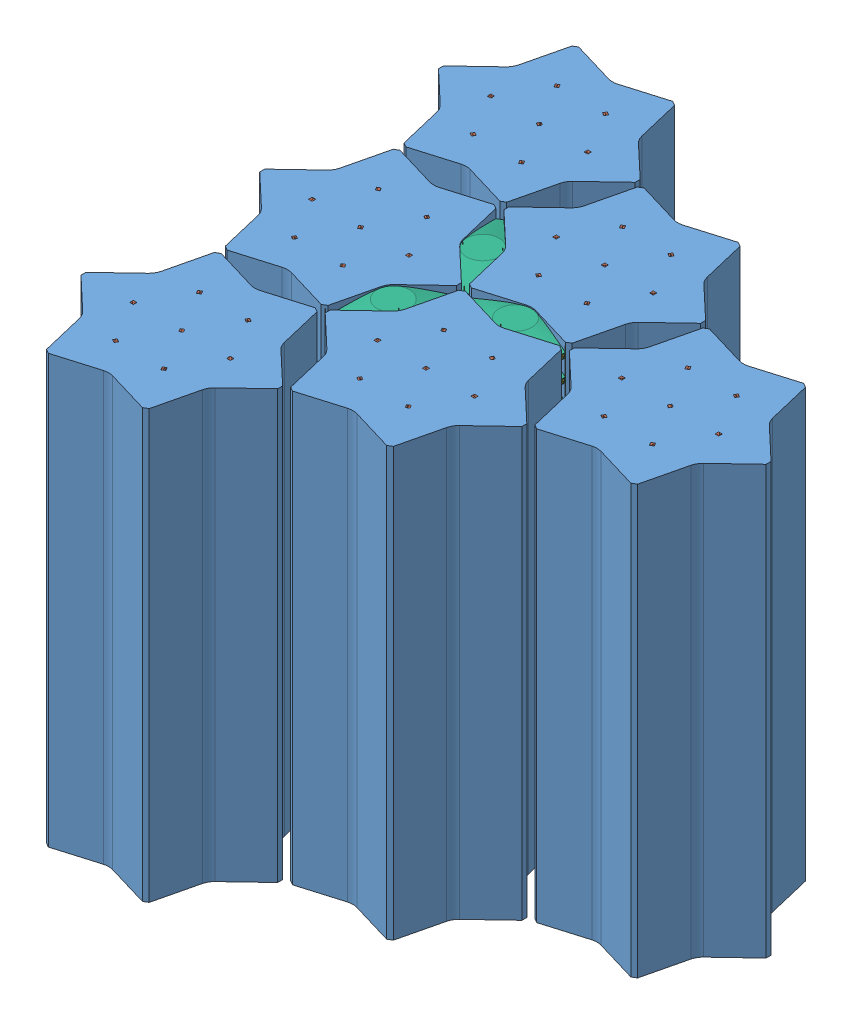
SolidWorks assembly Array-3, configuration 默认. Lengths in mm.
Overall size (1956.05 1510.25 2154.73).
477 component instances, 7 part files, 6 mates.
Components (placement in the parent):
- SArUnit-1: SArUnit [默认] at (117.0902 -977.6752 1500.5) size (690 1500.5 606.22)
  - SArContainer-1: SArContainer [默认] at origin size (690 1500 606.22)
  - SiPMArray-Ar-2: SiPMArray-Ar [默认] at (0 1500 0) size (12 0.5 12)
  - SiPMArray-Ar-3: SiPMArray-Ar [默认] at (-170 1500 0) size (12 0.5 12)
  - SiPMArray-Ar-4: SiPMArray-Ar [默认] at (-85 1500 147.2243) x (0.5 0 -0.866025) z (0.866025 0 0.5) size (12 0.5 12)
  - SiPMArray-Ar-5: SiPMArray-Ar [默认] at (85 1500 147.2243) x (-0.5 0 -0.866025) z (0.866025 0 -0.5) size (12 0.5 12)
  - SiPMArray-Ar-6: SiPMArray-Ar [默认] at (170 1500 0) x (-1 0 0) z (0 0 -1) size (12 0.5 12)
  - SiPMArray-Ar-7: SiPMArray-Ar [默认] at (85 1500 -147.2243) x (-0.5 0 0.866025) z (-0.866025 0 -0.5) size (12 0.5 12)
  - SiPMArray-Ar-8: SiPMArray-Ar [默认] at (-85 1500 -147.2243) x (0.5 0 0.866025) z (-0.866025 0 0.5) size (12 0.5 12)
- String-20-1: String-20 [默认] at (93.4968 -927.6636 1464.5499) x (1 0 0.000001) z (-0.000001 0 1) size (350.8 1510.25 116.67)
  - Unit-1: Unit [默认] at (24.7158 5.5651 269.4655) size (350.8 85.25 116.67)
    - BEGeDet-1: BEGeDet [默认] at (-1.1221 -39.076 80) size (80 40 80)
    - InnerShell-3: InnerShell [默认] at (-1.1221 11.4233 80) x (-1 0 0) z (0 0 1) size (102 61 102)
    - Electronics-1: Electronics [默认] at (-1.1221 -49.676 80) size (21.21 85 103.7)
    - OuterShell-2: OuterShell [默认] at (-1.1221 -55.5767 80) size (330 72.56 116.67)
    - SiPMArray-4: SiPMArray [默认] at (163.8779 -19.9292 80) size (10.4 81 12)
    - SiPMArray-6: SiPMArray [默认] at (-166.1221 -19.9292 80) x (-1 0 0) z (0 0 -1) size (10.4 81 12)
  - Unit-2: Unit [默认] at (24.7158 80.5651 269.4655) size (350.8 85.25 116.67)
    - BEGeDet-1: BEGeDet [默认] at (-1.1221 -39.076 80) size (80 40 80)
    - InnerShell-3: InnerShell [默认] at (-1.1221 11.4233 80) x (-1 0 0) z (0 0 1) size (102 61 102)
    - Electronics-1: Electronics [默认] at (-1.1221 -49.676 80) size (21.21 85 103.7)
    - OuterShell-2: OuterShell [默认] at (-1.1221 -55.5767 80) size (330 72.56 116.67)
    - SiPMArray-4: SiPMArray [默认] at (163.8779 -19.9292 80) size (10.4 81 12)
    - SiPMArray-6: SiPMArray [默认] at (-166.1221 -19.9292 80) x (-1 0 0) z (0 0 -1) size (10.4 81 12)
  - Unit-3: Unit [默认] at (24.7158 155.5651 269.4655) size (350.8 85.25 116.67)
    - BEGeDet-1: BEGeDet [默认] at (-1.1221 -39.076 80) size (80 40 80)
    - InnerShell-3: InnerShell [默认] at (-1.1221 11.4233 80) x (-1 0 0) z (0 0 1) size (102 61 102)
    - Electronics-1: Electronics [默认] at (-1.1221 -49.676 80) size (21.21 85 103.7)
    - OuterShell-2: OuterShell [默认] at (-1.1221 -55.5767 80) size (330 72.56 116.67)
    - SiPMArray-4: SiPMArray [默认] at (163.8779 -19.9292 80) size (10.4 81 12)
    - SiPMArray-6: SiPMArray [默认] at (-166.1221 -19.9292 80) x (-1 0 0) z (0 0 -1) size (10.4 81 12)
  - Unit-4: Unit [默认] at (24.7158 230.5651 269.4655) size (350.8 85.25 116.67)
    - BEGeDet-1: BEGeDet [默认] at (-1.1221 -39.076 80) size (80 40 80)
    - InnerShell-3: InnerShell [默认] at (-1.1221 11.4233 80) x (-1 0 0) z (0 0 1) size (102 61 102)
    - Electronics-1: Electronics [默认] at (-1.1221 -49.676 80) size (21.21 85 103.7)
    - OuterShell-2: OuterShell [默认] at (-1.1221 -55.5767 80) size (330 72.56 116.67)
    - SiPMArray-4: SiPMArray [默认] at (163.8779 -19.9292 80) size (10.4 81 12)
    - SiPMArray-6: SiPMArray [默认] at (-166.1221 -19.9292 80) x (-1 0 0) z (0 0 -1) size (10.4 81 12)
  - Unit-5: Unit [默认] at (24.7158 305.5651 269.4655) size (350.8 85.25 116.67)
    - BEGeDet-1: BEGeDet [默认] at (-1.1221 -39.076 80) size (80 40 80)
    - InnerShell-3: InnerShell [默认] at (-1.1221 11.4233 80) x (-1 0 0) z (0 0 1) size (102 61 102)
    - Electronics-1: Electronics [默认] at (-1.1221 -49.676 80) size (21.21 85 103.7)
    - OuterShell-2: OuterShell [默认] at (-1.1221 -55.5767 80) size (330 72.56 116.67)
    - SiPMArray-4: SiPMArray [默认] at (163.8779 -19.9292 80) size (10.4 81 12)
    - SiPMArray-6: SiPMArray [默认] at (-166.1221 -19.9292 80) x (-1 0 0) z (0 0 -1) size (10.4 81 12)
  - Unit-6: Unit [默认] at (24.7158 380.5651 269.4655) size (350.8 85.25 116.67)
    - BEGeDet-1: BEGeDet [默认] at (-1.1221 -39.076 80) size (80 40 80)
    - InnerShell-3: InnerShell [默认] at (-1.1221 11.4233 80) x (-1 0 0) z (0 0 1) size (102 61 102)
    - Electronics-1: Electronics [默认] at (-1.1221 -49.676 80) size (21.21 85 103.7)
    - OuterShell-2: OuterShell [默认] at (-1.1221 -55.5767 80) size (330 72.56 116.67)
    - SiPMArray-4: SiPMArray [默认] at (163.8779 -19.9292 80) size (10.4 81 12)
    - SiPMArray-6: SiPMArray [默认] at (-166.1221 -19.9292 80) x (-1 0 0) z (0 0 -1) size (10.4 81 12)
  - Unit-7: Unit [默认] at (24.7158 455.5651 269.4655) size (350.8 85.25 116.67)
    - BEGeDet-1: BEGeDet [默认] at (-1.1221 -39.076 80) size (80 40 80)
    - InnerShell-3: InnerShell [默认] at (-1.1221 11.4233 80) x (-1 0 0) z (0 0 1) size (102 61 102)
    - Electronics-1: Electronics [默认] at (-1.1221 -49.676 80) size (21.21 85 103.7)
    - OuterShell-2: OuterShell [默认] at (-1.1221 -55.5767 80) size (330 72.56 116.67)
    - SiPMArray-4: SiPMArray [默认] at (163.8779 -19.9292 80) size (10.4 81 12)
    - SiPMArray-6: SiPMArray [默认] at (-166.1221 -19.9292 80) x (-1 0 0) z (0 0 -1) size (10.4 81 12)
  - Unit-8: Unit [默认] at (24.7158 530.5651 269.4655) size (350.8 85.25 116.67)
    - BEGeDet-1: BEGeDet [默认] at (-1.1221 -39.076 80) size (80 40 80)
    - InnerShell-3: InnerShell [默认] at (-1.1221 11.4233 80) x (-1 0 0) z (0 0 1) size (102 61 102)
    - Electronics-1: Electronics [默认] at (-1.1221 -49.676 80) size (21.21 85 103.7)
    - OuterShell-2: OuterShell [默认] at (-1.1221 -55.5767 80) size (330 72.56 116.67)
    - SiPMArray-4: SiPMArray [默认] at (163.8779 -19.9292 80) size (10.4 81 12)
    - SiPMArray-6: SiPMArray [默认] at (-166.1221 -19.9292 80) x (-1 0 0) z (0 0 -1) size (10.4 81 12)
  - Unit-9: Unit [默认] at (24.7158 605.5651 269.4655) size (350.8 85.25 116.67)
    - BEGeDet-1: BEGeDet [默认] at (-1.1221 -39.076 80) size (80 40 80)
    - InnerShell-3: InnerShell [默认] at (-1.1221 11.4233 80) x (-1 0 0) z (0 0 1) size (102 61 102)
    - Electronics-1: Electronics [默认] at (-1.1221 -49.676 80) size (21.21 85 103.7)
    - OuterShell-2: OuterShell [默认] at (-1.1221 -55.5767 80) size (330 72.56 116.67)
    - SiPMArray-4: SiPMArray [默认] at (163.8779 -19.9292 80) size (10.4 81 12)
    - SiPMArray-6: SiPMArray [默认] at (-166.1221 -19.9292 80) x (-1 0 0) z (0 0 -1) size (10.4 81 12)
  - Unit-10: Unit [默认] at (24.7158 680.5651 269.4655) size (350.8 85.25 116.67)
    - BEGeDet-1: BEGeDet [默认] at (-1.1221 -39.076 80) size (80 40 80)
    - InnerShell-3: InnerShell [默认] at (-1.1221 11.4233 80) x (-1 0 0) z (0 0 1) size (102 61 102)
    - Electronics-1: Electronics [默认] at (-1.1221 -49.676 80) size (21.21 85 103.7)
    - OuterShell-2: OuterShell [默认] at (-1.1221 -55.5767 80) size (330 72.56 116.67)
    - SiPMArray-4: SiPMArray [默认] at (163.8779 -19.9292 80) size (10.4 81 12)
    - SiPMArray-6: SiPMArray [默认] at (-166.1221 -19.9292 80) x (-1 0 0) z (0 0 -1) size (10.4 81 12)
  - Unit-11: Unit [默认] at (24.7158 755.5651 269.4655) size (350.8 85.25 116.67)
    - BEGeDet-1: BEGeDet [默认] at (-1.1221 -39.076 80) size (80 40 80)
    - InnerShell-3: InnerShell [默认] at (-1.1221 11.4233 80) x (-1 0 0) z (0 0 1) size (102 61 102)
    - Electronics-1: Electronics [默认] at (-1.1221 -49.676 80) size (21.21 85 103.7)
    - OuterShell-2: OuterShell [默认] at (-1.1221 -55.5767 80) size (330 72.56 116.67)
    - SiPMArray-4: SiPMArray [默认] at (163.8779 -19.9292 80) size (10.4 81 12)
    - SiPMArray-6: SiPMArray [默认] at (-166.1221 -19.9292 80) x (-1 0 0) z (0 0 -1) size (10.4 81 12)
  - Unit-12: Unit [默认] at (24.7158 830.5651 269.4655) size (350.8 85.25 116.67)
    - BEGeDet-1: BEGeDet [默认] at (-1.1221 -39.076 80) size (80 40 80)
    - InnerShell-3: InnerShell [默认] at (-1.1221 11.4233 80) x (-1 0 0) z (0 0 1) size (102 61 102)
    - Electronics-1: Electronics [默认] at (-1.1221 -49.676 80) size (21.21 85 103.7)
    - OuterShell-2: OuterShell [默认] at (-1.1221 -55.5767 80) size (330 72.56 116.67)
    - SiPMArray-4: SiPMArray [默认] at (163.8779 -19.9292 80) size (10.4 81 12)
    - SiPMArray-6: SiPMArray [默认] at (-166.1221 -19.9292 80) x (-1 0 0) z (0 0 -1) size (10.4 81 12)
  - Unit-13: Unit [默认] at (24.7158 905.5651 269.4655) size (350.8 85.25 116.67)
    - BEGeDet-1: BEGeDet [默认] at (-1.1221 -39.076 80) size (80 40 80)
    - InnerShell-3: InnerShell [默认] at (-1.1221 11.4233 80) x (-1 0 0) z (0 0 1) size (102 61 102)
    - Electronics-1: Electronics [默认] at (-1.1221 -49.676 80) size (21.21 85 103.7)
    - OuterShell-2: OuterShell [默认] at (-1.1221 -55.5767 80) size (330 72.56 116.67)
    - SiPMArray-4: SiPMArray [默认] at (163.8779 -19.9292 80) size (10.4 81 12)
    - SiPMArray-6: SiPMArray [默认] at (-166.1221 -19.9292 80) x (-1 0 0) z (0 0 -1) size (10.4 81 12)
  - Unit-14: Unit [默认] at (24.7158 980.5651 269.4655) size (350.8 85.25 116.67)
    - BEGeDet-1: BEGeDet [默认] at (-1.1221 -39.076 80) size (80 40 80)
    - InnerShell-3: InnerShell [默认] at (-1.1221 11.4233 80) x (-1 0 0) z (0 0 1) size (102 61 102)
    - Electronics-1: Electronics [默认] at (-1.1221 -49.676 80) size (21.21 85 103.7)
    - OuterShell-2: OuterShell [默认] at (-1.1221 -55.5767 80) size (330 72.56 116.67)
    - SiPMArray-4: SiPMArray [默认] at (163.8779 -19.9292 80) size (10.4 81 12)
    - SiPMArray-6: SiPMArray [默认] at (-166.1221 -19.9292 80) x (-1 0 0) z (0 0 -1) size (10.4 81 12)
  - Unit-15: Unit [默认] at (24.7158 1055.5651 269.4655) size (350.8 85.25 116.67)
    - BEGeDet-1: BEGeDet [默认] at (-1.1221 -39.076 80) size (80 40 80)
    - InnerShell-3: InnerShell [默认] at (-1.1221 11.4233 80) x (-1 0 0) z (0 0 1) size (102 61 102)
    - Electronics-1: Electronics [默认] at (-1.1221 -49.676 80) size (21.21 85 103.7)
    - OuterShell-2: OuterShell [默认] at (-1.1221 -55.5767 80) size (330 72.56 116.67)
    - SiPMArray-4: SiPMArray [默认] at (163.8779 -19.9292 80) size (10.4 81 12)
    - SiPMArray-6: SiPMArray [默认] at (-166.1221 -19.9292 80) x (-1 0 0) z (0 0 -1) size (10.4 81 12)
  - Unit-16: Unit [默认] at (24.7158 1130.5651 269.4655) size (350.8 85.25 116.67)
    - BEGeDet-1: BEGeDet [默认] at (-1.1221 -39.076 80) size (80 40 80)
    - InnerShell-3: InnerShell [默认] at (-1.1221 11.4233 80) x (-1 0 0) z (0 0 1) size (102 61 102)
    - Electronics-1: Electronics [默认] at (-1.1221 -49.676 80) size (21.21 85 103.7)
    - OuterShell-2: OuterShell [默认] at (-1.1221 -55.5767 80) size (330 72.56 116.67)
    - SiPMArray-4: SiPMArray [默认] at (163.8779 -19.9292 80) size (10.4 81 12)
    - SiPMArray-6: SiPMArray [默认] at (-166.1221 -19.9292 80) x (-1 0 0) z (0 0 -1) size (10.4 81 12)
  - Unit-17: Unit [默认] at (24.7158 1205.5651 269.4655) size (350.8 85.25 116.67)
    - BEGeDet-1: BEGeDet [默认] at (-1.1221 -39.076 80) size (80 40 80)
    - InnerShell-3: InnerShell [默认] at (-1.1221 11.4233 80) x (-1 0 0) z (0 0 1) size (102 61 102)
    - Electronics-1: Electronics [默认] at (-1.1221 -49.676 80) size (21.21 85 103.7)
    - OuterShell-2: OuterShell [默认] at (-1.1221 -55.5767 80) size (330 72.56 116.67)
    - SiPMArray-4: SiPMArray [默认] at (163.8779 -19.9292 80) size (10.4 81 12)
    - SiPMArray-6: SiPMArray [默认] at (-166.1221 -19.9292 80) x (-1 0 0) z (0 0 -1) size (10.4 81 12)
  - Unit-18: Unit [默认] at (24.7158 1280.5651 269.4655) size (350.8 85.25 116.67)
    - BEGeDet-1: BEGeDet [默认] at (-1.1221 -39.076 80) size (80 40 80)
    - InnerShell-3: InnerShell [默认] at (-1.1221 11.4233 80) x (-1 0 0) z (0 0 1) size (102 61 102)
    - Electronics-1: Electronics [默认] at (-1.1221 -49.676 80) size (21.21 85 103.7)
    - OuterShell-2: OuterShell [默认] at (-1.1221 -55.5767 80) size (330 72.56 116.67)
    - SiPMArray-4: SiPMArray [默认] at (163.8779 -19.9292 80) size (10.4 81 12)
    - SiPMArray-6: SiPMArray [默认] at (-166.1221 -19.9292 80) x (-1 0 0) z (0 0 -1) size (10.4 81 12)
  - Unit-19: Unit [默认] at (24.7158 1355.5651 269.4655) size (350.8 85.25 116.67)
    - BEGeDet-1: BEGeDet [默认] at (-1.1221 -39.076 80) size (80 40 80)
    - InnerShell-3: InnerShell [默认] at (-1.1221 11.4233 80) x (-1 0 0) z (0 0 1) size (102 61 102)
    - Electronics-1: Electronics [默认] at (-1.1221 -49.676 80) size (21.21 85 103.7)
    - OuterShell-2: OuterShell [默认] at (-1.1221 -55.5767 80) size (330 72.56 116.67)
    - SiPMArray-4: SiPMArray [默认] at (163.8779 -19.9292 80) size (10.4 81 12)
    - SiPMArray-6: SiPMArray [默认] at (-166.1221 -19.9292 80) x (-1 0 0) z (0 0 -1) size (10.4 81 12)
  - Unit-20: Unit [默认] at (24.7158 1430.5651 269.4655) size (350.8 85.25 116.67)
    - BEGeDet-1: BEGeDet [默认] at (-1.1221 -39.076 80) size (80 40 80)
    - InnerShell-3: InnerShell [默认] at (-1.1221 11.4233 80) x (-1 0 0) z (0 0 1) size (102 61 102)
    - Electronics-1: Electronics [默认] at (-1.1221 -49.676 80) size (21.21 85 103.7)
    - OuterShell-2: OuterShell [默认] at (-1.1221 -55.5767 80) size (330 72.56 116.67)
    - SiPMArray-4: SiPMArray [默认] at (163.8779 -19.9292 80) size (10.4 81 12)
    - SiPMArray-6: SiPMArray [默认] at (-166.1221 -19.9292 80) x (-1 0 0) z (0 0 -1) size (10.4 81 12)
- SArUnit-2: SArUnit [默认] at (117.0902 -977.6752 2127.531) size (690 1500.5 606.22)
  - SArContainer-1: SArContainer [默认] at origin size (690 1500 606.22)
  - SiPMArray-Ar-2: SiPMArray-Ar [默认] at (0 1500 0) size (12 0.5 12)
  - SiPMArray-Ar-3: SiPMArray-Ar [默认] at (-170 1500 0) size (12 0.5 12)
  - SiPMArray-Ar-4: SiPMArray-Ar [默认] at (-85 1500 147.2243) x (0.5 0 -0.866025) z (0.866025 0 0.5) size (12 0.5 12)
  - SiPMArray-Ar-5: SiPMArray-Ar [默认] at (85 1500 147.2243) x (-0.5 0 -0.866025) z (0.866025 0 -0.5) size (12 0.5 12)
  - SiPMArray-Ar-6: SiPMArray-Ar [默认] at (170 1500 0) x (-1 0 0) z (0 0 -1) size (12 0.5 12)
  - SiPMArray-Ar-7: SiPMArray-Ar [默认] at (85 1500 -147.2243) x (-0.5 0 0.866025) z (-0.866025 0 -0.5) size (12 0.5 12)
  - SiPMArray-Ar-8: SiPMArray-Ar [默认] at (-85 1500 -147.2243) x (0.5 0 0.866025) z (-0.866025 0 0.5) size (12 0.5 12)
- String-20-2: String-20 [默认] at (-468.8649 -927.6636 1816.4729) x (0.500001 0 -0.866025) z (0.866025 0 0.500001) size (350.8 1510.25 116.67)
  - Unit-1: Unit [默认] at (24.7158 5.5651 269.4655) size (350.8 85.25 116.67)
    - BEGeDet-1: BEGeDet [默认] at (-1.1221 -39.076 80) size (80 40 80)
    - InnerShell-3: InnerShell [默认] at (-1.1221 11.4233 80) x (-1 0 0) z (0 0 1) size (102 61 102)
    - Electronics-1: Electronics [默认] at (-1.1221 -49.676 80) size (21.21 85 103.7)
    - OuterShell-2: OuterShell [默认] at (-1.1221 -55.5767 80) size (330 72.56 116.67)
    - SiPMArray-4: SiPMArray [默认] at (163.8779 -19.9292 80) size (10.4 81 12)
    - SiPMArray-6: SiPMArray [默认] at (-166.1221 -19.9292 80) x (-1 0 0) z (0 0 -1) size (10.4 81 12)
  - Unit-2: Unit [默认] at (24.7158 80.5651 269.4655) size (350.8 85.25 116.67)
    - BEGeDet-1: BEGeDet [默认] at (-1.1221 -39.076 80) size (80 40 80)
    - InnerShell-3: InnerShell [默认] at (-1.1221 11.4233 80) x (-1 0 0) z (0 0 1) size (102 61 102)
    - Electronics-1: Electronics [默认] at (-1.1221 -49.676 80) size (21.21 85 103.7)
    - OuterShell-2: OuterShell [默认] at (-1.1221 -55.5767 80) size (330 72.56 116.67)
    - SiPMArray-4: SiPMArray [默认] at (163.8779 -19.9292 80) size (10.4 81 12)
    - SiPMArray-6: SiPMArray [默认] at (-166.1221 -19.9292 80) x (-1 0 0) z (0 0 -1) size (10.4 81 12)
  - Unit-3: Unit [默认] at (24.7158 155.5651 269.4655) size (350.8 85.25 116.67)
    - BEGeDet-1: BEGeDet [默认] at (-1.1221 -39.076 80) size (80 40 80)
    - InnerShell-3: InnerShell [默认] at (-1.1221 11.4233 80) x (-1 0 0) z (0 0 1) size (102 61 102)
    - Electronics-1: Electronics [默认] at (-1.1221 -49.676 80) size (21.21 85 103.7)
    - OuterShell-2: OuterShell [默认] at (-1.1221 -55.5767 80) size (330 72.56 116.67)
    - SiPMArray-4: SiPMArray [默认] at (163.8779 -19.9292 80) size (10.4 81 12)
    - SiPMArray-6: SiPMArray [默认] at (-166.1221 -19.9292 80) x (-1 0 0) z (0 0 -1) size (10.4 81 12)
  - Unit-4: Unit [默认] at (24.7158 230.5651 269.4655) size (350.8 85.25 116.67)
    - BEGeDet-1: BEGeDet [默认] at (-1.1221 -39.076 80) size (80 40 80)
    - InnerShell-3: InnerShell [默认] at (-1.1221 11.4233 80) x (-1 0 0) z (0 0 1) size (102 61 102)
    - Electronics-1: Electronics [默认] at (-1.1221 -49.676 80) size (21.21 85 103.7)
    - OuterShell-2: OuterShell [默认] at (-1.1221 -55.5767 80) size (330 72.56 116.67)
    - SiPMArray-4: SiPMArray [默认] at (163.8779 -19.9292 80) size (10.4 81 12)
    - SiPMArray-6: SiPMArray [默认] at (-166.1221 -19.9292 80) x (-1 0 0) z (0 0 -1) size (10.4 81 12)
  - Unit-5: Unit [默认] at (24.7158 305.5651 269.4655) size (350.8 85.25 116.67)
    - BEGeDet-1: BEGeDet [默认] at (-1.1221 -39.076 80) size (80 40 80)
    - InnerShell-3: InnerShell [默认] at (-1.1221 11.4233 80) x (-1 0 0) z (0 0 1) size (102 61 102)
    - Electronics-1: Electronics [默认] at (-1.1221 -49.676 80) size (21.21 85 103.7)
    - OuterShell-2: OuterShell [默认] at (-1.1221 -55.5767 80) size (330 72.56 116.67)
    - SiPMArray-4: SiPMArray [默认] at (163.8779 -19.9292 80) size (10.4 81 12)
    - SiPMArray-6: SiPMArray [默认] at (-166.1221 -19.9292 80) x (-1 0 0) z (0 0 -1) size (10.4 81 12)
  - Unit-6: Unit [默认] at (24.7158 380.5651 269.4655) size (350.8 85.25 116.67)
    - BEGeDet-1: BEGeDet [默认] at (-1.1221 -39.076 80) size (80 40 80)
    - InnerShell-3: InnerShell [默认] at (-1.1221 11.4233 80) x (-1 0 0) z (0 0 1) size (102 61 102)
    - Electronics-1: Electronics [默认] at (-1.1221 -49.676 80) size (21.21 85 103.7)
    - OuterShell-2: OuterShell [默认] at (-1.1221 -55.5767 80) size (330 72.56 116.67)
    - SiPMArray-4: SiPMArray [默认] at (163.8779 -19.9292 80) size (10.4 81 12)
    - SiPMArray-6: SiPMArray [默认] at (-166.1221 -19.9292 80) x (-1 0 0) z (0 0 -1) size (10.4 81 12)
  - Unit-7: Unit [默认] at (24.7158 455.5651 269.4655) size (350.8 85.25 116.67)
    - BEGeDet-1: BEGeDet [默认] at (-1.1221 -39.076 80) size (80 40 80)
    - InnerShell-3: InnerShell [默认] at (-1.1221 11.4233 80) x (-1 0 0) z (0 0 1) size (102 61 102)
    - Electronics-1: Electronics [默认] at (-1.1221 -49.676 80) size (21.21 85 103.7)
    - OuterShell-2: OuterShell [默认] at (-1.1221 -55.5767 80) size (330 72.56 116.67)
    - SiPMArray-4: SiPMArray [默认] at (163.8779 -19.9292 80) size (10.4 81 12)
    - SiPMArray-6: SiPMArray [默认] at (-166.1221 -19.9292 80) x (-1 0 0) z (0 0 -1) size (10.4 81 12)
  - Unit-8: Unit [默认] at (24.7158 530.5651 269.4655) size (350.8 85.25 116.67)
    - BEGeDet-1: BEGeDet [默认] at (-1.1221 -39.076 80) size (80 40 80)
    - InnerShell-3: InnerShell [默认] at (-1.1221 11.4233 80) x (-1 0 0) z (0 0 1) size (102 61 102)
    - Electronics-1: Electronics [默认] at (-1.1221 -49.676 80) size (21.21 85 103.7)
    - OuterShell-2: OuterShell [默认] at (-1.1221 -55.5767 80) size (330 72.56 116.67)
    - SiPMArray-4: SiPMArray [默认] at (163.8779 -19.9292 80) size (10.4 81 12)
    - SiPMArray-6: SiPMArray [默认] at (-166.1221 -19.9292 80) x (-1 0 0) z (0 0 -1) size (10.4 81 12)
  - Unit-9: Unit [默认] at (24.7158 605.5651 269.4655) size (350.8 85.25 116.67)
    - BEGeDet-1: BEGeDet [默认] at (-1.1221 -39.076 80) size (80 40 80)
    - InnerShell-3: InnerShell [默认] at (-1.1221 11.4233 80) x (-1 0 0) z (0 0 1) size (102 61 102)
    - Electronics-1: Electronics [默认] at (-1.1221 -49.676 80) size (21.21 85 103.7)
    - OuterShell-2: OuterShell [默认] at (-1.1221 -55.5767 80) size (330 72.56 116.67)
    - SiPMArray-4: SiPMArray [默认] at (163.8779 -19.9292 80) size (10.4 81 12)
    - SiPMArray-6: SiPMArray [默认] at (-166.1221 -19.9292 80) x (-1 0 0) z (0 0 -1) size (10.4 81 12)
  - Unit-10: Unit [默认] at (24.7158 680.5651 269.4655) size (350.8 85.25 116.67)
    - BEGeDet-1: BEGeDet [默认] at (-1.1221 -39.076 80) size (80 40 80)
    - InnerShell-3: InnerShell [默认] at (-1.1221 11.4233 80) x (-1 0 0) z (0 0 1) size (102 61 102)
    - Electronics-1: Electronics [默认] at (-1.1221 -49.676 80) size (21.21 85 103.7)
    - OuterShell-2: OuterShell [默认] at (-1.1221 -55.5767 80) size (330 72.56 116.67)
    - SiPMArray-4: SiPMArray [默认] at (163.8779 -19.9292 80) size (10.4 81 12)
    - SiPMArray-6: SiPMArray [默认] at (-166.1221 -19.9292 80) x (-1 0 0) z (0 0 -1) size (10.4 81 12)
  - Unit-11: Unit [默认] at (24.7158 755.5651 269.4655) size (350.8 85.25 116.67)
    - BEGeDet-1: BEGeDet [默认] at (-1.1221 -39.076 80) size (80 40 80)
    - InnerShell-3: InnerShell [默认] at (-1.1221 11.4233 80) x (-1 0 0) z (0 0 1) size (102 61 102)
    - Electronics-1: Electronics [默认] at (-1.1221 -49.676 80) size (21.21 85 103.7)
    - OuterShell-2: OuterShell [默认] at (-1.1221 -55.5767 80) size (330 72.56 116.67)
    - SiPMArray-4: SiPMArray [默认] at (163.8779 -19.9292 80) size (10.4 81 12)
    - SiPMArray-6: SiPMArray [默认] at (-166.1221 -19.9292 80) x (-1 0 0) z (0 0 -1) size (10.4 81 12)
  - Unit-12: Unit [默认] at (24.7158 830.5651 269.4655) size (350.8 85.25 116.67)
    - BEGeDet-1: BEGeDet [默认] at (-1.1221 -39.076 80) size (80 40 80)
    - InnerShell-3: InnerShell [默认] at (-1.1221 11.4233 80) x (-1 0 0) z (0 0 1) size (102 61 102)
    - Electronics-1: Electronics [默认] at (-1.1221 -49.676 80) size (21.21 85 103.7)
    - OuterShell-2: OuterShell [默认] at (-1.1221 -55.5767 80) size (330 72.56 116.67)
    - SiPMArray-4: SiPMArray [默认] at (163.8779 -19.9292 80) size (10.4 81 12)
    - SiPMArray-6: SiPMArray [默认] at (-166.1221 -19.9292 80) x (-1 0 0) z (0 0 -1) size (10.4 81 12)
  - Unit-13: Unit [默认] at (24.7158 905.5651 269.4655) size (350.8 85.25 116.67)
    - BEGeDet-1: BEGeDet [默认] at (-1.1221 -39.076 80) size (80 40 80)
    - InnerShell-3: InnerShell [默认] at (-1.1221 11.4233 80) x (-1 0 0) z (0 0 1) size (102 61 102)
    - Electronics-1: Electronics [默认] at (-1.1221 -49.676 80) size (21.21 85 103.7)
    - OuterShell-2: OuterShell [默认] at (-1.1221 -55.5767 80) size (330 72.56 116.67)
    - SiPMArray-4: SiPMArray [默认] at (163.8779 -19.9292 80) size (10.4 81 12)
    - SiPMArray-6: SiPMArray [默认] at (-166.1221 -19.9292 80) x (-1 0 0) z (0 0 -1) size (10.4 81 12)
  - Unit-14: Unit [默认] at (24.7158 980.5651 269.4655) size (350.8 85.25 116.67)
    - BEGeDet-1: BEGeDet [默认] at (-1.1221 -39.076 80) size (80 40 80)
    - InnerShell-3: InnerShell [默认] at (-1.1221 11.4233 80) x (-1 0 0) z (0 0 1) size (102 61 102)
    - Electronics-1: Electronics [默认] at (-1.1221 -49.676 80) size (21.21 85 103.7)
    - OuterShell-2: OuterShell [默认] at (-1.1221 -55.5767 80) size (330 72.56 116.67)
    - SiPMArray-4: SiPMArray [默认] at (163.8779 -19.9292 80) size (10.4 81 12)
    - SiPMArray-6: SiPMArray [默认] at (-166.1221 -19.9292 80) x (-1 0 0) z (0 0 -1) size (10.4 81 12)
  - Unit-15: Unit [默认] at (24.7158 1055.5651 269.4655) size (350.8 85.25 116.67)
    - BEGeDet-1: BEGeDet [默认] at (-1.1221 -39.076 80) size (80 40 80)
    - InnerShell-3: InnerShell [默认] at (-1.1221 11.4233 80) x (-1 0 0) z (0 0 1) size (102 61 102)
    - Electronics-1: Electronics [默认] at (-1.1221 -49.676 80) size (21.21 85 103.7)
    - OuterShell-2: OuterShell [默认] at (-1.1221 -55.5767 80) size (330 72.56 116.67)
    - SiPMArray-4: SiPMArray [默认] at (163.8779 -19.9292 80) size (10.4 81 12)
    - SiPMArray-6: SiPMArray [默认] at (-166.1221 -19.9292 80) x (-1 0 0) z (0 0 -1) size (10.4 81 12)
  - Unit-16: Unit [默认] at (24.7158 1130.5651 269.4655) size (350.8 85.25 116.67)
    - BEGeDet-1: BEGeDet [默认] at (-1.1221 -39.076 80) size (80 40 80)
    - InnerShell-3: InnerShell [默认] at (-1.1221 11.4233 80) x (-1 0 0) z (0 0 1) size (102 61 102)
    - Electronics-1: Electronics [默认] at (-1.1221 -49.676 80) size (21.21 85 103.7)
    - OuterShell-2: OuterShell [默认] at (-1.1221 -55.5767 80) size (330 72.56 116.67)
    - SiPMArray-4: SiPMArray [默认] at (163.8779 -19.9292 80) size (10.4 81 12)
    - SiPMArray-6: SiPMArray [默认] at (-166.1221 -19.9292 80) x (-1 0 0) z (0 0 -1) size (10.4 81 12)
  - Unit-17: Unit [默认] at (24.7158 1205.5651 269.4655) size (350.8 85.25 116.67)
    - BEGeDet-1: BEGeDet [默认] at (-1.1221 -39.076 80) size (80 40 80)
    - InnerShell-3: InnerShell [默认] at (-1.1221 11.4233 80) x (-1 0 0) z (0 0 1) size (102 61 102)
    - Electronics-1: Electronics [默认] at (-1.1221 -49.676 80) size (21.21 85 103.7)
    - OuterShell-2: OuterShell [默认] at (-1.1221 -55.5767 80) size (330 72.56 116.67)
    - SiPMArray-4: SiPMArray [默认] at (163.8779 -19.9292 80) size (10.4 81 12)
    - SiPMArray-6: SiPMArray [默认] at (-166.1221 -19.9292 80) x (-1 0 0) z (0 0 -1) size (10.4 81 12)
  - Unit-18: Unit [默认] at (24.7158 1280.5651 269.4655) size (350.8 85.25 116.67)
    - BEGeDet-1: BEGeDet [默认] at (-1.1221 -39.076 80) size (80 40 80)
    - InnerShell-3: InnerShell [默认] at (-1.1221 11.4233 80) x (-1 0 0) z (0 0 1) size (102 61 102)
    - Electronics-1: Electronics [默认] at (-1.1221 -49.676 80) size (21.21 85 103.7)
    - OuterShell-2: OuterShell [默认] at (-1.1221 -55.5767 80) size (330 72.56 116.67)
    - SiPMArray-4: SiPMArray [默认] at (163.8779 -19.9292 80) size (10.4 81 12)
    - SiPMArray-6: SiPMArray [默认] at (-166.1221 -19.9292 80) x (-1 0 0) z (0 0 -1) size (10.4 81 12)
  - Unit-19: Unit [默认] at (24.7158 1355.5651 269.4655) size (350.8 85.25 116.67)
    - BEGeDet-1: BEGeDet [默认] at (-1.1221 -39.076 80) size (80 40 80)
    - InnerShell-3: InnerShell [默认] at (-1.1221 11.4233 80) x (-1 0 0) z (0 0 1) size (102 61 102)
    - Electronics-1: Electronics [默认] at (-1.1221 -49.676 80) size (21.21 85 103.7)
    - OuterShell-2: OuterShell [默认] at (-1.1221 -55.5767 80) size (330 72.56 116.67)
    - SiPMArray-4: SiPMArray [默认] at (163.8779 -19.9292 80) size (10.4 81 12)
    - SiPMArray-6: SiPMArray [默认] at (-166.1221 -19.9292 80) x (-1 0 0) z (0 0 -1) size (10.4 81 12)
  - Unit-20: Unit [默认] at (24.7158 1430.5651 269.4655) size (350.8 85.25 116.67)
    - BEGeDet-1: BEGeDet [默认] at (-1.1221 -39.076 80) size (80 40 80)
    - InnerShell-3: InnerShell [默认] at (-1.1221 11.4233 80) x (-1 0 0) z (0 0 1) size (102 61 102)
    - Electronics-1: Electronics [默认] at (-1.1221 -49.676 80) size (21.21 85 103.7)
    - OuterShell-2: OuterShell [默认] at (-1.1221 -55.5767 80) size (330 72.56 116.67)
    - SiPMArray-4: SiPMArray [默认] at (163.8779 -19.9292 80) size (10.4 81 12)
    - SiPMArray-6: SiPMArray [默认] at (-166.1221 -19.9292 80) x (-1 0 0) z (0 0 -1) size (10.4 81 12)
- String-20-3: String-20 [默认] at (136.4272 -927.6636 1462.0925) x (0.499999 0 0.866026) z (-0.866026 0 0.499999) size (350.8 1510.25 116.67)
  - Unit-1: Unit [默认] at (24.7158 5.5651 269.4655) size (350.8 85.25 116.67)
    - BEGeDet-1: BEGeDet [默认] at (-1.1221 -39.076 80) size (80 40 80)
    - InnerShell-3: InnerShell [默认] at (-1.1221 11.4233 80) x (-1 0 0) z (0 0 1) size (102 61 102)
    - Electronics-1: Electronics [默认] at (-1.1221 -49.676 80) size (21.21 85 103.7)
    - OuterShell-2: OuterShell [默认] at (-1.1221 -55.5767 80) size (330 72.56 116.67)
    - SiPMArray-4: SiPMArray [默认] at (163.8779 -19.9292 80) size (10.4 81 12)
    - SiPMArray-6: SiPMArray [默认] at (-166.1221 -19.9292 80) x (-1 0 0) z (0 0 -1) size (10.4 81 12)
  - Unit-2: Unit [默认] at (24.7158 80.5651 269.4655) size (350.8 85.25 116.67)
    - BEGeDet-1: BEGeDet [默认] at (-1.1221 -39.076 80) size (80 40 80)
    - InnerShell-3: InnerShell [默认] at (-1.1221 11.4233 80) x (-1 0 0) z (0 0 1) size (102 61 102)
    - Electronics-1: Electronics [默认] at (-1.1221 -49.676 80) size (21.21 85 103.7)
    - OuterShell-2: OuterShell [默认] at (-1.1221 -55.5767 80) size (330 72.56 116.67)
    - SiPMArray-4: SiPMArray [默认] at (163.8779 -19.9292 80) size (10.4 81 12)
    - SiPMArray-6: SiPMArray [默认] at (-166.1221 -19.9292 80) x (-1 0 0) z (0 0 -1) size (10.4 81 12)
  - Unit-3: Unit [默认] at (24.7158 155.5651 269.4655) size (350.8 85.25 116.67)
    - BEGeDet-1: BEGeDet [默认] at (-1.1221 -39.076 80) size (80 40 80)
    - InnerShell-3: InnerShell [默认] at (-1.1221 11.4233 80) x (-1 0 0) z (0 0 1) size (102 61 102)
    - Electronics-1: Electronics [默认] at (-1.1221 -49.676 80) size (21.21 85 103.7)
    - OuterShell-2: OuterShell [默认] at (-1.1221 -55.5767 80) size (330 72.56 116.67)
    - SiPMArray-4: SiPMArray [默认] at (163.8779 -19.9292 80) size (10.4 81 12)
    - SiPMArray-6: SiPMArray [默认] at (-166.1221 -19.9292 80) x (-1 0 0) z (0 0 -1) size (10.4 81 12)
  - Unit-4: Unit [默认] at (24.7158 230.5651 269.4655) size (350.8 85.25 116.67)
    - BEGeDet-1: BEGeDet [默认] at (-1.1221 -39.076 80) size (80 40 80)
    - InnerShell-3: InnerShell [默认] at (-1.1221 11.4233 80) x (-1 0 0) z (0 0 1) size (102 61 102)
    - Electronics-1: Electronics [默认] at (-1.1221 -49.676 80) size (21.21 85 103.7)
    - OuterShell-2: OuterShell [默认] at (-1.1221 -55.5767 80) size (330 72.56 116.67)
    - SiPMArray-4: SiPMArray [默认] at (163.8779 -19.9292 80) size (10.4 81 12)
    - SiPMArray-6: SiPMArray [默认] at (-166.1221 -19.9292 80) x (-1 0 0) z (0 0 -1) size (10.4 81 12)
  - Unit-5: Unit [默认] at (24.7158 305.5651 269.4655) size (350.8 85.25 116.67)
    - BEGeDet-1: BEGeDet [默认] at (-1.1221 -39.076 80) size (80 40 80)
    - InnerShell-3: InnerShell [默认] at (-1.1221 11.4233 80) x (-1 0 0) z (0 0 1) size (102 61 102)
    - Electronics-1: Electronics [默认] at (-1.1221 -49.676 80) size (21.21 85 103.7)
    - OuterShell-2: OuterShell [默认] at (-1.1221 -55.5767 80) size (330 72.56 116.67)
    - SiPMArray-4: SiPMArray [默认] at (163.8779 -19.9292 80) size (10.4 81 12)
    - SiPMArray-6: SiPMArray [默认] at (-166.1221 -19.9292 80) x (-1 0 0) z (0 0 -1) size (10.4 81 12)
  - Unit-6: Unit [默认] at (24.7158 380.5651 269.4655) size (350.8 85.25 116.67)
    - BEGeDet-1: BEGeDet [默认] at (-1.1221 -39.076 80) size (80 40 80)
    - InnerShell-3: InnerShell [默认] at (-1.1221 11.4233 80) x (-1 0 0) z (0 0 1) size (102 61 102)
    - Electronics-1: Electronics [默认] at (-1.1221 -49.676 80) size (21.21 85 103.7)
    - OuterShell-2: OuterShell [默认] at (-1.1221 -55.5767 80) size (330 72.56 116.67)
    - SiPMArray-4: SiPMArray [默认] at (163.8779 -19.9292 80) size (10.4 81 12)
    - SiPMArray-6: SiPMArray [默认] at (-166.1221 -19.9292 80) x (-1 0 0) z (0 0 -1) size (10.4 81 12)
  - Unit-7: Unit [默认] at (24.7158 455.5651 269.4655) size (350.8 85.25 116.67)
    - BEGeDet-1: BEGeDet [默认] at (-1.1221 -39.076 80) size (80 40 80)
    - InnerShell-3: InnerShell [默认] at (-1.1221 11.4233 80) x (-1 0 0) z (0 0 1) size (102 61 102)
    - Electronics-1: Electronics [默认] at (-1.1221 -49.676 80) size (21.21 85 103.7)
    - OuterShell-2: OuterShell [默认] at (-1.1221 -55.5767 80) size (330 72.56 116.67)
    - SiPMArray-4: SiPMArray [默认] at (163.8779 -19.9292 80) size (10.4 81 12)
    - SiPMArray-6: SiPMArray [默认] at (-166.1221 -19.9292 80) x (-1 0 0) z (0 0 -1) size (10.4 81 12)
  - Unit-8: Unit [默认] at (24.7158 530.5651 269.4655) size (350.8 85.25 116.67)
    - BEGeDet-1: BEGeDet [默认] at (-1.1221 -39.076 80) size (80 40 80)
    - InnerShell-3: InnerShell [默认] at (-1.1221 11.4233 80) x (-1 0 0) z (0 0 1) size (102 61 102)
    - Electronics-1: Electronics [默认] at (-1.1221 -49.676 80) size (21.21 85 103.7)
    - OuterShell-2: OuterShell [默认] at (-1.1221 -55.5767 80) size (330 72.56 116.67)
    - SiPMArray-4: SiPMArray [默认] at (163.8779 -19.9292 80) size (10.4 81 12)
    - SiPMArray-6: SiPMArray [默认] at (-166.1221 -19.9292 80) x (-1 0 0) z (0 0 -1) size (10.4 81 12)
  - Unit-9: Unit [默认] at (24.7158 605.5651 269.4655) size (350.8 85.25 116.67)
    - BEGeDet-1: BEGeDet [默认] at (-1.1221 -39.076 80) size (80 40 80)
    - InnerShell-3: InnerShell [默认] at (-1.1221 11.4233 80) x (-1 0 0) z (0 0 1) size (102 61 102)
    - Electronics-1: Electronics [默认] at (-1.1221 -49.676 80) size (21.21 85 103.7)
    - OuterShell-2: OuterShell [默认] at (-1.1221 -55.5767 80) size (330 72.56 116.67)
    - SiPMArray-4: SiPMArray [默认] at (163.8779 -19.9292 80) size (10.4 81 12)
    - SiPMArray-6: SiPMArray [默认] at (-166.1221 -19.9292 80) x (-1 0 0) z (0 0 -1) size (10.4 81 12)
  - Unit-10: Unit [默认] at (24.7158 680.5651 269.4655) size (350.8 85.25 116.67)
    - BEGeDet-1: BEGeDet [默认] at (-1.1221 -39.076 80) size (80 40 80)
    - InnerShell-3: InnerShell [默认] at (-1.1221 11.4233 80) x (-1 0 0) z (0 0 1) size (102 61 102)
    - Electronics-1: Electronics [默认] at (-1.1221 -49.676 80) size (21.21 85 103.7)
    - OuterShell-2: OuterShell [默认] at (-1.1221 -55.5767 80) size (330 72.56 116.67)
    - SiPMArray-4: SiPMArray [默认] at (163.8779 -19.9292 80) size (10.4 81 12)
    - SiPMArray-6: SiPMArray [默认] at (-166.1221 -19.9292 80) x (-1 0 0) z (0 0 -1) size (10.4 81 12)
  - Unit-11: Unit [默认] at (24.7158 755.5651 269.4655) size (350.8 85.25 116.67)
    - BEGeDet-1: BEGeDet [默认] at (-1.1221 -39.076 80) size (80 40 80)
    - InnerShell-3: InnerShell [默认] at (-1.1221 11.4233 80) x (-1 0 0) z (0 0 1) size (102 61 102)
    - Electronics-1: Electronics [默认] at (-1.1221 -49.676 80) size (21.21 85 103.7)
    - OuterShell-2: OuterShell [默认] at (-1.1221 -55.5767 80) size (330 72.56 116.67)
    - SiPMArray-4: SiPMArray [默认] at (163.8779 -19.9292 80) size (10.4 81 12)
    - SiPMArray-6: SiPMArray [默认] at (-166.1221 -19.9292 80) x (-1 0 0) z (0 0 -1) size (10.4 81 12)
  - Unit-12: Unit [默认] at (24.7158 830.5651 269.4655) size (350.8 85.25 116.67)
    - BEGeDet-1: BEGeDet [默认] at (-1.1221 -39.076 80) size (80 40 80)
    - InnerShell-3: InnerShell [默认] at (-1.1221 11.4233 80) x (-1 0 0) z (0 0 1) size (102 61 102)
    - Electronics-1: Electronics [默认] at (-1.1221 -49.676 80) size (21.21 85 103.7)
    - OuterShell-2: OuterShell [默认] at (-1.1221 -55.5767 80) size (330 72.56 116.67)
    - SiPMArray-4: SiPMArray [默认] at (163.8779 -19.9292 80) size (10.4 81 12)
    - SiPMArray-6: SiPMArray [默认] at (-166.1221 -19.9292 80) x (-1 0 0) z (0 0 -1) size (10.4 81 12)
  - Unit-13: Unit [默认] at (24.7158 905.5651 269.4655) size (350.8 85.25 116.67)
    - BEGeDet-1: BEGeDet [默认] at (-1.1221 -39.076 80) size (80 40 80)
    - InnerShell-3: InnerShell [默认] at (-1.1221 11.4233 80) x (-1 0 0) z (0 0 1) size (102 61 102)
    - Electronics-1: Electronics [默认] at (-1.1221 -49.676 80) size (21.21 85 103.7)
    - OuterShell-2: OuterShell [默认] at (-1.1221 -55.5767 80) size (330 72.56 116.67)
    - SiPMArray-4: SiPMArray [默认] at (163.8779 -19.9292 80) size (10.4 81 12)
    - SiPMArray-6: SiPMArray [默认] at (-166.1221 -19.9292 80) x (-1 0 0) z (0 0 -1) size (10.4 81 12)
  - Unit-14: Unit [默认] at (24.7158 980.5651 269.4655) size (350.8 85.25 116.67)
    - BEGeDet-1: BEGeDet [默认] at (-1.1221 -39.076 80) size (80 40 80)
    - InnerShell-3: InnerShell [默认] at (-1.1221 11.4233 80) x (-1 0 0) z (0 0 1) size (102 61 102)
    - Electronics-1: Electronics [默认] at (-1.1221 -49.676 80) size (21.21 85 103.7)
    - OuterShell-2: OuterShell [默认] at (-1.1221 -55.5767 80) size (330 72.56 116.67)
    - SiPMArray-4: SiPMArray [默认] at (163.8779 -19.9292 80) size (10.4 81 12)
    - SiPMArray-6: SiPMArray [默认] at (-166.1221 -19.9292 80) x (-1 0 0) z (0 0 -1) size (10.4 81 12)
  - Unit-15: Unit [默认] at (24.7158 1055.5651 269.4655) size (350.8 85.25 116.67)
    - BEGeDet-1: BEGeDet [默认] at (-1.1221 -39.076 80) size (80 40 80)
    - InnerShell-3: InnerShell [默认] at (-1.1221 11.4233 80) x (-1 0 0) z (0 0 1) size (102 61 102)
    - Electronics-1: Electronics [默认] at (-1.1221 -49.676 80) size (21.21 85 103.7)
    - OuterShell-2: OuterShell [默认] at (-1.1221 -55.5767 80) size (330 72.56 116.67)
    - SiPMArray-4: SiPMArray [默认] at (163.8779 -19.9292 80) size (10.4 81 12)
    - SiPMArray-6: SiPMArray [默认] at (-166.1221 -19.9292 80) x (-1 0 0) z (0 0 -1) size (10.4 81 12)
  - Unit-16: Unit [默认] at (24.7158 1130.5651 269.4655) size (350.8 85.25 116.67)
    - BEGeDet-1: BEGeDet [默认] at (-1.1221 -39.076 80) size (80 40 80)
    - InnerShell-3: InnerShell [默认] at (-1.1221 11.4233 80) x (-1 0 0) z (0 0 1) size (102 61 102)
    - Electronics-1: Electronics [默认] at (-1.1221 -49.676 80) size (21.21 85 103.7)
    - OuterShell-2: OuterShell [默认] at (-1.1221 -55.5767 80) size (330 72.56 116.67)
    - SiPMArray-4: SiPMArray [默认] at (163.8779 -19.9292 80) size (10.4 81 12)
    - SiPMArray-6: SiPMArray [默认] at (-166.1221 -19.9292 80) x (-1 0 0) z (0 0 -1) size (10.4 81 12)
  - Unit-17: Unit [默认] at (24.7158 1205.5651 269.4655) size (350.8 85.25 116.67)
    - BEGeDet-1: BEGeDet [默认] at (-1.1221 -39.076 80) size (80 40 80)
    - InnerShell-3: InnerShell [默认] at (-1.1221 11.4233 80) x (-1 0 0) z (0 0 1) size (102 61 102)
    - Electronics-1: Electronics [默认] at (-1.1221 -49.676 80) size (21.21 85 103.7)
    - OuterShell-2: OuterShell [默认] at (-1.1221 -55.5767 80) size (330 72.56 116.67)
    - SiPMArray-4: SiPMArray [默认] at (163.8779 -19.9292 80) size (10.4 81 12)
    - SiPMArray-6: SiPMArray [默认] at (-166.1221 -19.9292 80) x (-1 0 0) z (0 0 -1) size (10.4 81 12)
  - Unit-18: Unit [默认] at (24.7158 1280.5651 269.4655) size (350.8 85.25 116.67)
    - BEGeDet-1: BEGeDet [默认] at (-1.1221 -39.076 80) size (80 40 80)
    - InnerShell-3: InnerShell [默认] at (-1.1221 11.4233 80) x (-1 0 0) z (0 0 1) size (102 61 102)
    - Electronics-1: Electronics [默认] at (-1.1221 -49.676 80) size (21.21 85 103.7)
    - OuterShell-2: OuterShell [默认] at (-1.1221 -55.5767 80) size (330 72.56 116.67)
    - SiPMArray-4: SiPMArray [默认] at (163.8779 -19.9292 80) size (10.4 81 12)
    - SiPMArray-6: SiPMArray [默认] at (-166.1221 -19.9292 80) x (-1 0 0) z (0 0 -1) size (10.4 81 12)
  - Unit-19: Unit [默认] at (24.7158 1355.5651 269.4655) size (350.8 85.25 116.67)
    - BEGeDet-1: BEGeDet [默认] at (-1.1221 -39.076 80) size (80 40 80)
    - InnerShell-3: InnerShell [默认] at (-1.1221 11.4233 80) x (-1 0 0) z (0 0 1) size (102 61 102)
    - Electronics-1: Electronics [默认] at (-1.1221 -49.676 80) size (21.21 85 103.7)
    - OuterShell-2: OuterShell [默认] at (-1.1221 -55.5767 80) size (330 72.56 116.67)
    - SiPMArray-4: SiPMArray [默认] at (163.8779 -19.9292 80) size (10.4 81 12)
    - SiPMArray-6: SiPMArray [默认] at (-166.1221 -19.9292 80) x (-1 0 0) z (0 0 -1) size (10.4 81 12)
  - Unit-20: Unit [默认] at (24.7158 1430.5651 269.4655) size (350.8 85.25 116.67)
    - BEGeDet-1: BEGeDet [默认] at (-1.1221 -39.076 80) size (80 40 80)
    - InnerShell-3: InnerShell [默认] at (-1.1221 11.4233 80) x (-1 0 0) z (0 0 1) size (102 61 102)
    - Electronics-1: Electronics [默认] at (-1.1221 -49.676 80) size (21.21 85 103.7)
    - OuterShell-2: OuterShell [默认] at (-1.1221 -55.5767 80) size (330 72.56 116.67)
    - SiPMArray-4: SiPMArray [默认] at (163.8779 -19.9292 80) size (10.4 81 12)
    - SiPMArray-6: SiPMArray [默认] at (-166.1221 -19.9292 80) x (-1 0 0) z (0 0 -1) size (10.4 81 12)
- SArUnit-3: SArUnit [默认] at (-425.9345 -977.6752 1814.0155) x (0.5 0 0.866025) z (-0.866025 0 0.5) size (690 1500.5 606.22)
  - SArContainer-1: SArContainer [默认] at origin size (690 1500 606.22)
  - SiPMArray-Ar-2: SiPMArray-Ar [默认] at (0 1500 0) size (12 0.5 12)
  - SiPMArray-Ar-3: SiPMArray-Ar [默认] at (-170 1500 0) size (12 0.5 12)
  - SiPMArray-Ar-4: SiPMArray-Ar [默认] at (-85 1500 147.2243) x (0.5 0 -0.866025) z (0.866025 0 0.5) size (12 0.5 12)
  - SiPMArray-Ar-5: SiPMArray-Ar [默认] at (85 1500 147.2243) x (-0.5 0 -0.866025) z (0.866025 0 -0.5) size (12 0.5 12)
  - SiPMArray-Ar-6: SiPMArray-Ar [默认] at (170 1500 0) x (-1 0 0) z (0 0 -1) size (12 0.5 12)
  - SiPMArray-Ar-7: SiPMArray-Ar [默认] at (85 1500 -147.2243) x (-0.5 0 0.866025) z (-0.866025 0 -0.5) size (12 0.5 12)
  - SiPMArray-Ar-8: SiPMArray-Ar [默认] at (-85 1500 -147.2243) x (0.5 0 0.866025) z (-0.866025 0 0.5) size (12 0.5 12)
- SArUnit-4: SArUnit [默认] at (-425.9345 -977.6752 1186.9845) x (-0.5 0 0.866025) z (-0.866025 0 -0.5) size (690 1500.5 606.22)
  - SArContainer-1: SArContainer [默认] at origin size (690 1500 606.22)
  - SiPMArray-Ar-2: SiPMArray-Ar [默认] at (0 1500 0) size (12 0.5 12)
  - SiPMArray-Ar-3: SiPMArray-Ar [默认] at (-170 1500 0) size (12 0.5 12)
  - SiPMArray-Ar-4: SiPMArray-Ar [默认] at (-85 1500 147.2243) x (0.5 0 -0.866025) z (0.866025 0 0.5) size (12 0.5 12)
  - SiPMArray-Ar-5: SiPMArray-Ar [默认] at (85 1500 147.2243) x (-0.5 0 -0.866025) z (0.866025 0 -0.5) size (12 0.5 12)
  - SiPMArray-Ar-6: SiPMArray-Ar [默认] at (170 1500 0) x (-1 0 0) z (0 0 -1) size (12 0.5 12)
  - SiPMArray-Ar-7: SiPMArray-Ar [默认] at (85 1500 -147.2243) x (-0.5 0 0.866025) z (-0.866025 0 -0.5) size (12 0.5 12)
  - SiPMArray-Ar-8: SiPMArray-Ar [默认] at (-85 1500 -147.2243) x (0.5 0 0.866025) z (-0.866025 0 0.5) size (12 0.5 12)
- SArUnit-5: SArUnit [默认] at (660.115 -977.6752 1814.0155) x (0.5 0 -0.866025) z (0.866025 0 0.5) size (690 1500.5 606.22)
  - SArContainer-1: SArContainer [默认] at origin size (690 1500 606.22)
  - SiPMArray-Ar-2: SiPMArray-Ar [默认] at (0 1500 0) size (12 0.5 12)
  - SiPMArray-Ar-3: SiPMArray-Ar [默认] at (-170 1500 0) size (12 0.5 12)
  - SiPMArray-Ar-4: SiPMArray-Ar [默认] at (-85 1500 147.2243) x (0.5 0 -0.866025) z (0.866025 0 0.5) size (12 0.5 12)
  - SiPMArray-Ar-5: SiPMArray-Ar [默认] at (85 1500 147.2243) x (-0.5 0 -0.866025) z (0.866025 0 -0.5) size (12 0.5 12)
  - SiPMArray-Ar-6: SiPMArray-Ar [默认] at (170 1500 0) x (-1 0 0) z (0 0 -1) size (12 0.5 12)
  - SiPMArray-Ar-7: SiPMArray-Ar [默认] at (85 1500 -147.2243) x (-0.5 0 0.866025) z (-0.866025 0 -0.5) size (12 0.5 12)
  - SiPMArray-Ar-8: SiPMArray-Ar [默认] at (-85 1500 -147.2243) x (0.5 0 0.866025) z (-0.866025 0 0.5) size (12 0.5 12)
- SArUnit-6: SArUnit [默认] at (-425.9345 -977.6752 2441.0464) x (0.5 0 0.866025) z (-0.866025 0 0.5) size (690 1500.5 606.22)
  - SArContainer-1: SArContainer [默认] at origin size (690 1500 606.22)
  - SiPMArray-Ar-2: SiPMArray-Ar [默认] at (0 1500 0) size (12 0.5 12)
  - SiPMArray-Ar-3: SiPMArray-Ar [默认] at (-170 1500 0) size (12 0.5 12)
  - SiPMArray-Ar-4: SiPMArray-Ar [默认] at (-85 1500 147.2243) x (0.5 0 -0.866025) z (0.866025 0 0.5) size (12 0.5 12)
  - SiPMArray-Ar-5: SiPMArray-Ar [默认] at (85 1500 147.2243) x (-0.5 0 -0.866025) z (0.866025 0 -0.5) size (12 0.5 12)
  - SiPMArray-Ar-6: SiPMArray-Ar [默认] at (170 1500 0) x (-1 0 0) z (0 0 -1) size (12 0.5 12)
  - SiPMArray-Ar-7: SiPMArray-Ar [默认] at (85 1500 -147.2243) x (-0.5 0 0.866025) z (-0.866025 0 -0.5) size (12 0.5 12)
  - SiPMArray-Ar-8: SiPMArray-Ar [默认] at (-85 1500 -147.2243) x (0.5 0 0.866025) z (-0.866025 0 0.5) size (12 0.5 12)
Mates (geometry in assembly coordinates):
- 重合1: coincident aligned: plane of SArUnit-1/SArContainer-1 through (117.0902 -977.6752 1500.5) normal (0 -1 0); plane of String-20-1/Unit-1/OuterShell-2 through (117.0902 -977.6752 1814.0155) normal (0 -1 0)
- 重合2: coincident anti-aligned: plane of SArUnit-1/SArContainer-1 through (282.0902 522.3248 1803.6089) normal (-0.285001 0 0.958527); plane of String-20-1/Unit-20/OuterShell-2 through (133.3353 616.3248 1759.3794) normal (0.285001 0 -0.958527)
- 同心1: concentric anti-aligned: circle of SArUnit-1/SArContainer-1; circle of String-20-1/Unit-20/OuterShell-2
- 重合4: coincident aligned: plane of SArUnit-1/SArContainer-1 through (117.0902 -977.6752 1500.5) normal (0 -1 0); plane of SArUnit-2/SArContainer-1 through (117.0902 -977.6752 2127.531) normal (0 -1 0)
- 重合5: coincident anti-aligned: plane of String-20-1/Unit-20/OuterShell-2 through (100.8452 616.3248 1868.6515) normal (-0.285001 0 0.958527); plane of SArUnit-2/SArContainer-1 through (-47.9098 522.3248 1824.4221) normal (0.285001 0 -0.958527)
- 同心2: concentric anti-aligned: circle of String-20-1/Unit-20/OuterShell-2; circle of SArUnit-2/SArContainer-1
